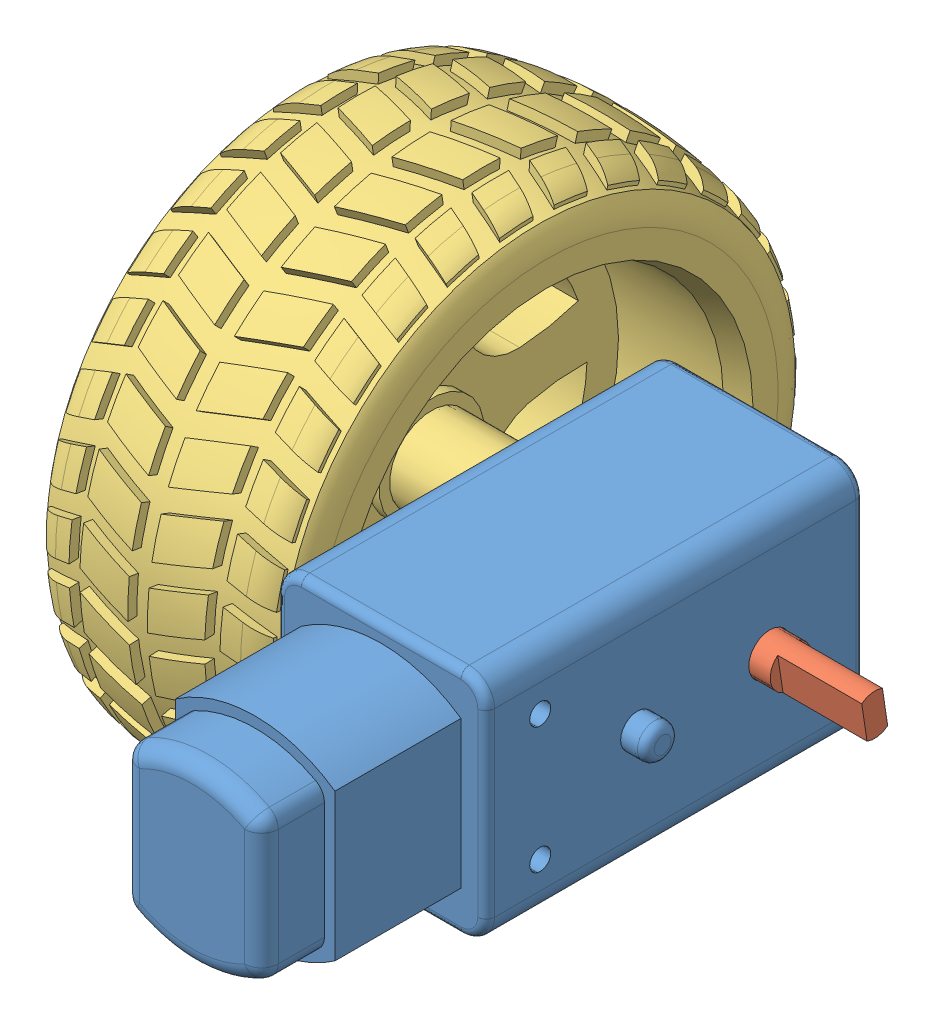
SolidWorks assembly Wheel+motor+shaft+screw, configuration Wheel with L shape. Lengths in mm.
Overall size (69 77.84 95.15).
3 component instances, 3 part files, 8 mates.
Components (placement in the parent):
- motor-1: motor [Default] at (-176.6436 24.9401 31.3103)
- shaft-1: shaft [Default] at (-201.6436 24.9401 42.5603) x (1 0 0) z (0 0.988792 0.1493)
- wheel (scaled)-1: wheel (scaled) [Default] at (-205.6436 24.9401 42.5603) x (1 0 0) z (0 -0.988792 -0.1493)
Mates (geometry in assembly coordinates):
- Concentric1: concentric anti-aligned: cylinder of motor-1 through (-189.1436 24.9401 42.5603) axis (1 0 0) radius 2.5; cylinder of shaft-1 through (-151.6436 24.9401 42.5603) axis (-1 0 0) radius 2.45
- Width2: width aligned: plane of shaft-1 through (-201.6436 24.9401 42.5603) normal (-1 0 0); plane of shaft-1 through (-151.6436 24.9401 42.5603) normal (1 0 0); plane of motor-1 through (-189.1436 35.6901 76.3103) normal (-1 0 0); plane of motor-1 through (-164.1436 35.6901 76.3103) normal (1 0 0)
- Concentric2: concentric aligned: cylinder of shaft-1 through (-151.6436 24.9401 42.5603) axis (-1 0 0) radius 2.45; cylinder of wheel (scaled)-1 through (-215.6436 24.9401 42.5603) axis (-1 0 0) radius 2.5
- Width3: width aligned: plane of shaft-1 through (-191.6436 24.7543 43.7913) normal (0 -0.1493 0.988792); plane of shaft-1 through (-191.6436 25.126 41.3292) normal (0 0.1493 -0.988792); plane of wheel (scaled)-1 through (-217.6506 22.986 41.0011) normal (0 -0.1493 0.988792); plane of wheel (scaled)-1 through (-217.6506 22.6127 43.473) normal (0 0.1493 -0.988792)
- Distance1: distance = 1.5 mm anti-aligned: plane of wheel (scaled)-1 through (-193.1436 24.5669 45.0323) normal (1 0 0); plane of shaft-1 through (-191.6436 24.9401 42.5603) normal (-1 0 0)
- Coincident1: coincident anti-aligned: axis of motor-1 through (-162.1436 24.9401 58.3103) axis (-1 0 0); axis of ? through (-164.1436 24.9401 58.3103) axis (1 0 0)
- Parallel1: parallel aligned: plane of motor-1 through (-167.1436 35.6901 76.3103) normal (0 0 1); plane of ? through (-164.1436 70.9401 70.8103) normal (0 0 1)
- Coincident2: coincident anti-aligned: plane of motor-1 through (-164.1436 35.6901 76.3103) normal (1 0 0); plane of ? through (-164.1436 40.9401 58.3103) normal (-1 0 0)
